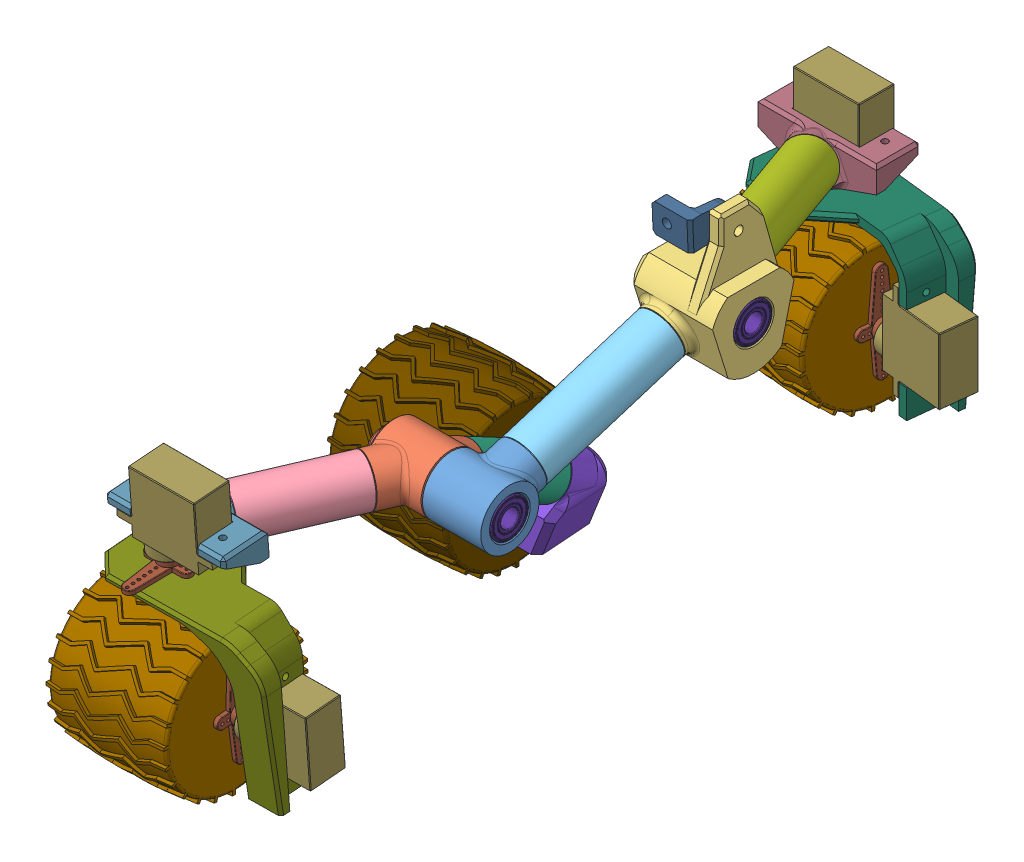
SolidWorks assembly suspensionSub-left[moving], configuration Default. Lengths in mm.
Overall size (94.09 139.66 290.69).
30 component instances, 18 part files, 68 mates.
Components (placement in the parent):
- bogieJointFixed-left-1: bogieJointFixed-left [Default] at (-58.6456 10.5337 84.2533) x (0 0.297904 -0.954596) z (1 0 0) size (40 20 21.53)
- bogieJointFree-left-1: bogieJointFree-left [Default] at (-79.1456 10.5337 84.2533) x (1 0 0) z (0 0.469272 0.883054) size (27.04 27.37 57.25)
- rockerJoint-left-1: rockerJoint-left [Default] at (-51.1456 34.3124 8.0574) x (1 0 0) z (0 -0.297904 0.954596) size (35.64 50.55 55.79)
- aftBogieTube-1: aftBogieTube [Default] at (-108.56 11.4559 132.6244) x (0.903071 0.237373 0.357934) z (-0.213924 0.971258 -0.10438) size (15.88 37.13 15.88)
- aftRockerTube-1: aftRockerTube [Default] at (-68.6456 15.0022 69.9343) x (0.5 -0.826704 -0.257992) z (0.866025 0.477298 0.148952) size (15.88 49.82 15.88)
- foreBogieTube-1: foreBogieTube [Default] at (-89.1456 3.4946 71.0075) x (0.998082 0.054659 -0.029047) z (-0.061898 0.881361 -0.468372) size (15.88 33.7 15.88)
- foreRockerTube-1: foreRockerTube [Default] at (-106.955 16.1877 -66.6715) x (0.695295 -0.693645 -0.188204) z (-0.563663 -0.688728 0.456002) size (15.88 70.91 15.88)
- wheelStrut-mid-right-1: wheelStrut-mid-right [Default] at (-119.2029 -26.7316 35.9191) x (1 0 0) z (0 -0.075549 0.997142) size (23.13 36.67 28.96)
- tire-1: tire [Default] at (-113.6439 -30.2768 -79.7193) x (-0.020281 0.982539 0.184946) z (-0.994041 0 -0.109007) size (53.45 55.85 40.12)
- tire-3: tire [Default] at (-114.1463 -34.8452 143.0147) x (0.001646 0.973073 0.230492) z (-0.999945 -0.000795 0.010498) size (53.45 55.85 40.12)
- rodHinge-sus-left-1: rodHinge-sus-left [Default] at (-62.1456 34.3403 7.0424) x (0 0.33642 -0.941712) z (1 0 0) size (15.98 12.99 13)
- sg90ServoHorn-star-1: sg90ServoHorn-star [Default] at (-111.018 4.7232 -77.5199) x (0.109007 0 -0.994041) z (0.994041 0 0.109007) size (34.4 4 15.7)
- sg90ServoHorn-star-2: sg90ServoHorn-star [Default] at (-117.0162 0.196 143.7944) x (0.010528 -0.075545 0.997087) z (-0.999945 -0.000795 0.010498) size (34.4 4 15.7)
- sg90ServoHorn-star-3: sg90ServoHorn-star [Default] at (-94.1178 -33.0979 145.76) x (0.000185 -0.998315 -0.058028) z (0.010526 -0.058023 0.99826) size (34.4 4 15.7)
- sg90ServoHorn-star-4: sg90ServoHorn-star [Default] at (-94.0764 -28.4129 -74.6825) x (0.001375 -0.99992 -0.012537) z (-0.108998 -0.012612 0.993962) size (34.4 4 15.7)
- sg90Servo-1: sg90Servo [Default] at (-119.8963 31.3989 141.8661) x (1 0 0) z (0 0.075549 -0.997142) size (32.7 29.37 12.3)
- sg90Servo-2: sg90Servo [Default] at (-63.1164 -41.0029 148.1773) x (0 0.997142 0.075549) z (0.010528 -0.075545 0.997087) size (32.7 29.37 12.3)
- sg90Servo-3: sg90Servo [Default] at (-63.65 -36.0268 -68.0501) x (0 1 0) z (-0.109007 0 0.994041) size (32.7 29.37 12.3)
- sg90Servo-4: sg90Servo [Default] at (-119.3939 35.6912 -85.8693) x (1 0 0) z (0 0 -1) size (32.7 29.37 12.3)
- wheelPivot-front-left-v2-1: wheelPivot-front-left-v2 [Default] at (-119.3939 35.6912 -67.5693) x (1 0 0) z (0 0 -1) size (40.7 16.47 34.17)
- wheelPivot-rear-left-v2-1: wheelPivot-rear-left-v2 [Default] at (-119.8963 31.8522 135.8832) x (-1 0 0) z (0 -0.075549 0.997142) size (40.7 18.75 35.49)
- wheelStrut-front-left-v2-1: wheelStrut-front-left-v2 [Default] at (-64.9908 -36.0268 -55.8233) x (0 1 0) z (-0.109007 0 0.994041) size (50.75 59.16 31.22)
- wheelStrut-rear-left-v2-1: wheelStrut-rear-left-v2 [Default] at (-63.3754 -39.1445 123.649) x (0 0.997142 0.075549) z (0.010528 -0.075545 0.997087) size (50.75 59.16 31.22)
- 6x13x5BearingShielded-1: 6x13x5BearingShielded [Default] at (-56.1456 34.3124 8.0574) x (0 -0.920758 0.390135) z (0 0.390135 0.920758) size (13 5 13)
- 6x13x5BearingShielded-2: 6x13x5BearingShielded [Default] at (-76.1456 34.3124 8.0574) x (0 1 0) z (0 0 1) size (13 5 13)
- 6x13x5BearingShielded-3: 6x13x5BearingShielded [Default] at (-73.6456 10.5337 84.2533) x (0 1 0) z (0 0 1) size (13 5 13)
- 6x13x5BearingShielded-4: 6x13x5BearingShielded [Default] at (-63.6456 10.5337 84.2533) x (0 -1 0) z (0 0 1) size (13 5 13)
- tire-mid-1: tire-mid [Default] at (-125.1743 -26.7316 35.9191) x (0 0.956404 0.292046) z (-1 0 0) size (53.45 55.85 40.12)
- 6x13x5BearingShielded-5: 6x13x5BearingShielded [Default] at (-110.1743 -26.7316 35.9191) x (0 -1 0) z (0 0 1) size (13 5 13)
- 6x13x5BearingShielded-6: 6x13x5BearingShielded [Default] at (-135.1743 -26.7316 35.9191) x (0 -1 0) z (0 0 1) size (13 5 13)
Mates (geometry in assembly coordinates):
- Parallel1: parallel aligned: plane of rockerJoint-left-1 through (-81.1466 46.3124 8.0574) normal (0 1 0); plane of assembly through (0 0 0) normal (0 1 0)
- Concentric3: concentric aligned: line of rockerJoint-left-1 through (-68.6456 34.3124 8.0574) axis (-0.445925 -0.210972 -0.869851); cylinder of foreRockerTube-1 through (-75.3345 31.1478 -4.9903) axis (-0.445925 -0.210972 -0.869851) radius 7.94
- Coincident4: coincident anti-aligned: plane of rockerJoint-left-1 through (-75.3345 31.1478 -4.9903) normal (-0.445925 -0.210972 -0.869851); plane of foreRockerTube-1 through (-75.3345 31.1478 -4.9903) normal (0.445925 0.210972 0.869851)
- Concentric4: concentric anti-aligned: line of rockerJoint-left-1 through (-68.6456 9.9222 86.2125) axis (0 0.297904 -0.954596); cylinder of aftRockerTube-1 through (-68.6456 29.8438 22.3764) axis (0 -0.297904 0.954596) radius 7.94
- Coincident5: coincident anti-aligned: plane of rockerJoint-left-1 through (-68.6456 29.8438 22.3764) normal (0 -0.297904 0.954596); plane of aftRockerTube-1 through (-68.6456 29.8438 22.3764) normal (0 0.297904 -0.954596)
- Concentric5: concentric aligned: line of bogieJointFixed-left-1 through (-68.6456 15.0022 69.9343) axis (0 -0.297904 0.954596); cylinder of aftRockerTube-1 through (-68.6456 29.8438 22.3764) axis (0 -0.297904 0.954596) radius 7.94
- Coincident6: coincident anti-aligned: plane of bogieJointFixed-left-1 through (-68.6456 15.0022 69.9343) normal (0 0.297904 -0.954596); plane of aftRockerTube-1 through (-68.6456 15.0022 69.9343) normal (0 -0.297904 0.954596)
- Concentric6: concentric anti-aligned: line of bogieJointFree-left-1 through (-89.1456 10.5337 84.2533) axis (0 -0.469272 -0.883054); cylinder of foreBogieTube-1 through (-89.1456 -12.3199 41.2485) axis (0 0.469272 0.883054) radius 7.94
- Coincident9: coincident anti-aligned: plane of bogieJointFree-left-1 through (-89.1456 3.4946 71.0075) normal (0 -0.469272 -0.883054); plane of foreBogieTube-1 through (-89.1456 3.4946 71.0075) normal (0 0.469272 0.883054)
- Concentric8: concentric anti-aligned: line of bogieJointFree-left-1 through (-114.1456 11.7213 146.541) axis (0.372423 -0.017692 -0.927895); cylinder of aftBogieTube-1 through (-94.732 10.799 98.1717) axis (-0.372423 0.017692 0.927895) radius 7.94
- Coincident11: coincident anti-aligned: plane of bogieJointFree-left-1 through (-94.732 10.799 98.1717) normal (-0.372423 0.017692 0.927895); plane of aftBogieTube-1 through (-94.732 10.799 98.1717) normal (0.372423 -0.017692 -0.927895)
- Concentric12: concentric anti-aligned: cylinder of foreBogieTube-1 through (-89.1456 -12.3199 41.2485) axis (0 0.469272 0.883054) radius 7.94; line of wheelStrut-mid-right-1 through (-89.1456 10.5333 84.2526) axis (0 -0.469272 -0.883054)
- Coincident14: coincident anti-aligned: plane of foreBogieTube-1 through (-89.1456 -12.3199 41.2485) normal (0 -0.469272 -0.883054); plane of wheelStrut-mid-right-1 through (-89.1456 -12.3199 41.2485) normal (0 0.469272 0.883054)
- Distance6: distance = 1 mm anti-aligned: plane of rockerJoint-left-1 through (-61.1456 40.2303 22.2025) normal (-1 0 0); plane of rodHinge-sus-left-1 through (-62.1456 34.3403 7.0424) normal (1 0 0)
- Concentric18: concentric anti-aligned: cylinder of rockerJoint-left-1 through (-51.1446 59.3124 8.2384) axis (-1 0 0) radius 1.55; cylinder of rodHinge-sus-left-1 through (-65.1456 59.3124 8.2384) axis (1 0 0) radius 1.55
- Concentric20: concentric aligned: cylinder of foreRockerTube-1 through (-75.3345 31.1478 -4.9903) axis (-0.445925 -0.210972 -0.869851) radius 7.94; cylinder of wheelPivot-front-left-v2-1 through (-106.955 16.1877 -66.6715) axis (-0.445925 -0.210972 -0.869851) radius 7.94
- Coincident46: coincident anti-aligned: plane of foreRockerTube-1 through (-106.955 16.1877 -66.6715) normal (-0.445925 -0.210972 -0.869851); plane of wheelPivot-front-left-v2-1 through (-106.955 16.1877 -66.6715) normal (0.445925 0.210972 0.869851)
- Parallel2: parallel aligned: plane of rockerJoint-left-1 through (-81.1466 46.3124 8.0574) normal (0 1 0); plane of wheelPivot-front-left-v2-1 through (-119.3939 23.0662 -70.5693) normal (0 1 0)
- Coincident48: coincident aligned: line of sg90Servo-4 through (-96.4439 20.0662 -85.6193) axis (0 0 1); line of wheelPivot-front-left-v2-1 through (-96.4439 20.0662 -85.8693) axis (0 0 1)
- Coincident49: coincident anti-aligned: line of sg90Servo-4 through (-119.6439 20.0662 -73.8193) axis (0 0 -1); line of wheelPivot-front-left-v2-1 through (-119.6439 20.0662 -85.8693) axis (0 0 1)
- Coincident50: coincident anti-aligned: plane of sg90Servo-4 through (-119.3939 13.4662 -73.5693) normal (0 0 1); plane of wheelPivot-front-left-v2-1 through (-119.3939 35.6912 -73.5693) normal (0 0 -1)
- Concentric21: concentric aligned: cylinder of aftBogieTube-1 through (-94.732 10.799 98.1717) axis (-0.372423 0.017692 0.927895) radius 7.94; cylinder of wheelPivot-rear-left-v2-1 through (-108.56 11.4559 132.6244) axis (-0.372423 0.017692 0.927895) radius 7.94
- Coincident51: coincident anti-aligned: plane of aftBogieTube-1 through (-108.56 11.4559 132.6244) normal (-0.372423 0.017692 0.927895); plane of wheelPivot-rear-left-v2-1 through (-108.56 11.4559 132.6244) normal (0.372423 -0.017692 -0.927895)
- Coincident53: coincident aligned: line of sg90Servo-1 through (-120.1463 14.9081 152.7012) axis (0 0.075549 -0.997142); line of wheelPivot-rear-left-v2-1 through (-120.1463 14.8893 152.9505) axis (0 0.075549 -0.997142)
- Coincident54: coincident anti-aligned: line of sg90Servo-1 through (-96.9463 15.7996 140.9349) axis (0 -0.075549 0.997142); line of wheelPivot-rear-left-v2-1 through (-96.9463 14.8893 152.9505) axis (0 0.075549 -0.997142)
- Coincident55: coincident anti-aligned: plane of sg90Servo-1 through (-119.8963 9.2374 140.187) normal (0 0.075549 -0.997142); plane of wheelPivot-rear-left-v2-1 through (-119.8963 31.3989 141.8661) normal (0 -0.075549 0.997142)
- Coincident56: coincident anti-aligned: plane of sg90ServoHorn-star-1 through (-111.018 4.7232 -77.5199) normal (0 -1 0); plane of wheelStrut-front-left-v2-1 through (-61.5462 4.7232 -87.235) normal (0 1 0)
- Concentric22: concentric aligned: cylinder of sg90ServoHorn-star-1 through (-113.6439 4.7222 -79.7193) axis (0 1 0) radius 1.2; cylinder of wheelStrut-front-left-v2-1 through (-113.6439 -46.0279 -79.7193) axis (0 1 0) radius 2.4
- Coincident58: coincident anti-aligned: plane of sg90ServoHorn-star-2 through (-117.0162 0.196 143.7944) normal (0 -0.997142 -0.075549); plane of wheelStrut-rear-left-v2-1 through (-63.0427 -0.8981 158.2355) normal (0 0.997142 0.075549)
- Concentric23: concentric aligned: cylinder of sg90ServoHorn-star-2 through (-114.1463 0.0537 145.6588) axis (0 0.997142 0.075549) radius 1.2; cylinder of wheelStrut-rear-left-v2-1 through (-114.1463 -50.5512 141.8247) axis (0 0.997142 0.075549) radius 2.4
- Concentric24: concentric aligned: cylinder of sg90ServoHorn-star-1 through (-113.6439 6.3232 -79.7193) axis (0 1 0) radius 2.4; cylinder of sg90Servo-4 through (-113.6439 6.3232 -79.7193) axis (0 1 0) radius 1.984
- Coincident60: coincident anti-aligned: plane of sg90ServoHorn-star-1 through (-113.6439 6.3232 -79.7193) normal (0 1 0); plane of sg90Servo-4 through (-113.6439 6.3232 -79.7193) normal (0 -1 0)
- Concentric25: concentric aligned: cylinder of sg90ServoHorn-star-2 through (-114.1463 1.6502 145.7798) axis (0 0.997142 0.075549) radius 2.4; cylinder of sg90Servo-1 through (-114.1463 1.6502 145.7798) axis (0 0.997142 0.075549) radius 1.984
- Coincident61: coincident anti-aligned: plane of sg90ServoHorn-star-2 through (-114.1463 1.6502 145.7798) normal (0 0.997142 0.075549); plane of sg90Servo-1 through (-114.1463 1.6502 145.7798) normal (0 -0.997142 -0.075549)
- Coincident63: coincident anti-aligned: plane of tire-3 through (-94.108 -11.478 148.336) normal (0.999945 0.000795 -0.010498); plane of sg90ServoHorn-star-3 through (-94.1178 -33.0979 145.76) normal (-0.999945 -0.000795 0.010498)
- Concentric26: concentric anti-aligned: line of tire-3 through (-92.1476 -34.8277 142.7837) axis (-0.999945 -0.000795 0.010498); cylinder of sg90ServoHorn-star-3 through (-94.1485 -34.8293 142.8047) axis (0.999945 0.000795 -0.010498) radius 1.2
- Coincident64: coincident anti-aligned: line of sg90Servo-2 through (-78.7432 -18.112 149.8259) axis (-0.010528 0.075545 -0.997087); line of wheelStrut-rear-left-v2-1 through (-78.8701 -17.2017 137.811) axis (0.010528 -0.075545 0.997087)
- Coincident65: coincident aligned: line of sg90Servo-2 through (-78.8674 -40.3543 136.3075) axis (0.010528 -0.075545 0.997087); line of wheelStrut-rear-left-v2-1 through (-78.8701 -40.3354 136.0583) axis (0.010528 -0.075545 0.997087)
- Coincident66: coincident anti-aligned: plane of sg90Servo-2 through (-85.3402 -41.0205 148.4106) normal (0.010528 -0.075545 0.997087); plane of wheelStrut-rear-left-v2-1 through (-63.1164 -41.0029 148.1773) normal (-0.010528 0.075545 -0.997087)
- Concentric28: concentric aligned: cylinder of sg90ServoHorn-star-3 through (-92.5475 -34.8281 142.7879) axis (0.999945 0.000795 -0.010498) radius 2.4; cylinder of sg90Servo-2 through (-92.5475 -34.8281 142.7879) axis (0.999945 0.000795 -0.010498) radius 1.984
- Coincident67: coincident anti-aligned: plane of sg90ServoHorn-star-3 through (-92.5475 -34.8281 142.7879) normal (0.999945 0.000795 -0.010498); plane of sg90Servo-2 through (-92.5475 -34.8281 142.7879) normal (-0.999945 -0.000795 0.010498)
- Coincident68: coincident anti-aligned: plane of tire-1 through (-94.2498 -6.6984 -73.1009) normal (0.994041 0 0.109007); plane of sg90ServoHorn-star-4 through (-94.0764 -28.4129 -74.6825) normal (-0.994041 0 -0.109007)
- Concentric30: concentric anti-aligned: line of tire-1 through (-91.775 -30.2768 -77.3211) axis (-0.994041 0 -0.109007); cylinder of sg90ServoHorn-star-4 through (-93.7641 -30.2768 -77.5392) axis (0.994041 0 0.109007) radius 1.2
- Coincident69: coincident aligned: line of sg90Servo-3 through (-79.1547 -13.0768 -70.0018) axis (0.109007 0 -0.994041); line of wheelStrut-front-left-v2-1 through (-79.1819 -13.0768 -69.7533) axis (0.109007 0 -0.994041)
- Coincident70: coincident anti-aligned: line of sg90Servo-3 through (-77.8684 -36.2768 -81.7315) axis (-0.109007 0 0.994041); line of wheelStrut-front-left-v2-1 through (-79.1819 -36.2768 -69.7533) axis (0.109007 0 -0.994041)
- Coincident71: coincident anti-aligned: plane of sg90Servo-3 through (-84.4018 -36.0268 -82.6994) normal (0.109007 0 -0.994041); plane of wheelStrut-front-left-v2-1 through (-62.3092 -36.0268 -80.2768) normal (-0.109007 0 0.994041)
- Concentric33: concentric aligned: cylinder of sg90ServoHorn-star-4 through (-92.1726 -30.2768 -77.3647) axis (0.994041 0 0.109007) radius 2.4; cylinder of sg90Servo-3 through (-92.1726 -30.2768 -77.3647) axis (0.994041 0 0.109007) radius 1.984
- Coincident72: coincident anti-aligned: plane of sg90ServoHorn-star-4 through (-92.1726 -30.2768 -77.3647) normal (0.994041 0 0.109007); plane of sg90Servo-3 through (-92.1726 -30.2768 -77.3647) normal (-0.994041 0 -0.109007)
- Concentric34: concentric anti-aligned: cylinder of rockerJoint-left-1 through (-75.1456 34.3124 8.0574) axis (-1 0 0) radius 6.5; cylinder of 6x13x5BearingShielded-2 through (-81.1456 34.3124 8.0574) axis (1 0 0) radius 6.5
- Coincident73: coincident aligned: plane of rockerJoint-left-1 through (-81.1456 34.3124 8.0574) normal (-1 0 0); plane of 6x13x5BearingShielded-2 through (-81.1456 34.3124 8.0574) normal (-1 0 0)
- Concentric35: concentric anti-aligned: cylinder of rockerJoint-left-1 through (-57.1456 34.3124 8.0574) axis (1 0 0) radius 6.5; cylinder of 6x13x5BearingShielded-1 through (-51.1456 34.3124 8.0574) axis (-1 0 0) radius 6.5
- Coincident74: coincident aligned: plane of rockerJoint-left-1 through (-51.1456 34.3124 8.0574) normal (1 0 0); plane of 6x13x5BearingShielded-1 through (-51.1456 34.3124 8.0574) normal (1 0 0)
- Concentric37: concentric anti-aligned: cylinder of bogieJointFixed-left-1 through (-64.6456 10.5337 84.2533) axis (1 0 0) radius 6.5; cylinder of 6x13x5BearingShielded-4 through (-58.6456 10.5337 84.2533) axis (-1 0 0) radius 6.5
- Coincident75: coincident aligned: plane of bogieJointFixed-left-1 through (-58.6456 10.5337 84.2533) normal (1 0 0); plane of 6x13x5BearingShielded-4 through (-58.6456 10.5337 84.2533) normal (1 0 0)
- Concentric38: concentric anti-aligned: cylinder of bogieJointFixed-left-1 through (-72.6456 10.5337 84.2533) axis (-1 0 0) radius 6.5; cylinder of 6x13x5BearingShielded-3 through (-78.6456 10.5337 84.2533) axis (1 0 0) radius 6.5
- Coincident76: coincident aligned: plane of bogieJointFixed-left-1 through (-78.6456 10.5337 84.2533) normal (-1 0 0); plane of 6x13x5BearingShielded-3 through (-78.6456 10.5337 84.2533) normal (-1 0 0)
- Concentric39: concentric aligned: cylinder of bogieJointFixed-left-1 through (-78.6456 10.5337 84.2533) axis (1 0 0) radius 10; cylinder of bogieJointFree-left-1 through (-99.1456 10.5337 84.2533) axis (1 0 0) radius 10
- Distance7: distance = 0.5 mm anti-aligned: plane of bogieJointFree-left-1 through (-79.1456 10.5337 84.2533) normal (1 0 0); plane of bogieJointFixed-left-1 through (-78.6456 10.5337 84.2533) normal (-1 0 0)
- Concentric40: concentric aligned: cylinder of wheelStrut-mid-right-1 through (-76.2571 -26.7316 35.9191) axis (-1 0 0) radius 3; cylinder of tire-mid-1 through (-105.1146 -26.7316 35.9191) axis (-1 0 0) radius 3.75
- Distance8: distance = 1 mm anti-aligned: plane of tire-mid-1 through (-105.1743 -3.7803 42.9275) normal (1 0 0); plane of wheelStrut-mid-right-1 through (-104.1743 -27.4871 45.8905) normal (-1 0 0)
- Concentric41: concentric anti-aligned: cylinder of tire-mid-1 through (-111.1743 -26.7316 35.9191) axis (1 0 0) radius 6.5; cylinder of 6x13x5BearingShielded-5 through (-105.1743 -26.7316 35.9191) axis (-1 0 0) radius 6.5
- Coincident79: coincident aligned: plane of tire-mid-1 through (-105.1743 -3.7803 42.9275) normal (1 0 0); plane of 6x13x5BearingShielded-5 through (-105.1743 -26.7316 35.9191) normal (1 0 0)
- Concentric42: concentric aligned: cylinder of tire-mid-1 through (-129.1743 -26.7316 35.9191) axis (-1 0 0) radius 6.5; cylinder of 6x13x5BearingShielded-6 through (-130.1743 -26.7316 35.9191) axis (-1 0 0) radius 6.5
- Coincident80: coincident aligned: plane of tire-mid-1 through (-135.1743 -26.7316 35.9191) normal (-1 0 0); plane of 6x13x5BearingShielded-6 through (-135.1743 -26.7316 35.9191) normal (-1 0 0)
- Concentric45: concentric aligned: cylinder of tire-3 through (-104.5639 -19.8629 143.7845) axis (0.999945 0.000795 -0.010498) radius 0.5; cylinder of sg90ServoHorn-star-3 through (-94.1512 -19.8546 143.6752) axis (0.999945 0.000795 -0.010498) radius 0.5
- Concentric46: concentric aligned: cylinder of tire-1 through (-104.1359 -15.278 -78.4863) axis (0.994041 0 0.109007) radius 0.5; cylinder of sg90ServoHorn-star-4 through (-93.7847 -15.278 -77.3512) axis (0.994041 0 0.109007) radius 0.5
- Concentric47: concentric aligned: cylinder of sg90ServoHorn-star-2 through (-114.2411 0.7336 136.685) axis (0 0.997142 0.075549) radius 0.5; cylinder of wheelStrut-rear-left-v2-1 through (-114.2411 -49.8713 132.8509) axis (0 0.997142 0.075549) radius 0.5
- Concentric48: concentric aligned: cylinder of sg90ServoHorn-star-1 through (-114.625 4.7222 -70.7729) axis (0 1 0) radius 0.5; cylinder of wheelStrut-front-left-v2-1 through (-114.625 -46.0279 -70.7729) axis (0 1 0) radius 0.5
